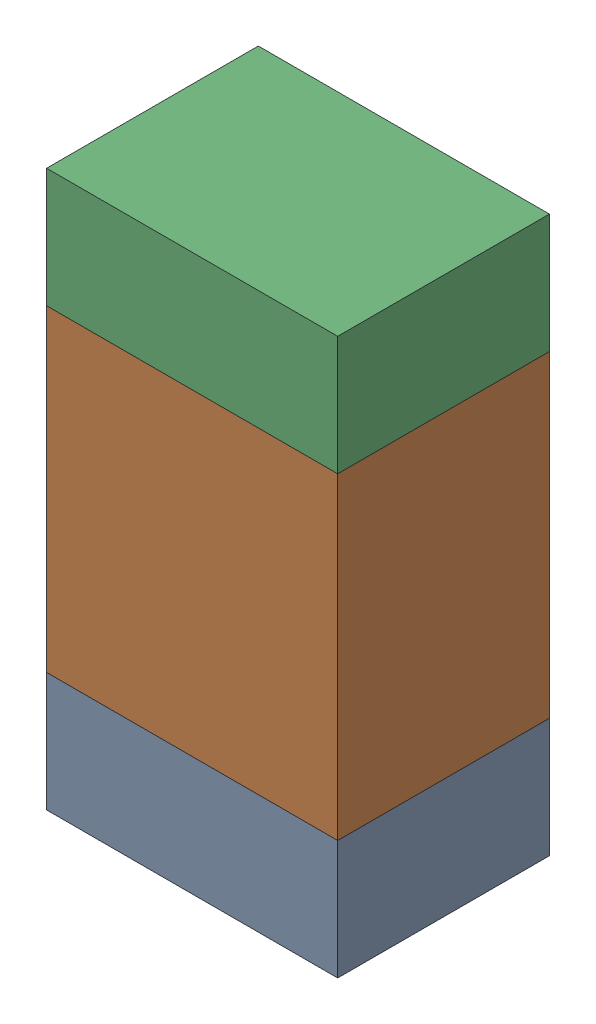
SolidWorks assembly R301_1PCB, configuration Default. Lengths in mm.
Overall size (0.55 1.05 0.4).
6 component instances, 2 part files, 0 mates.
Components (placement in the parent):
- 846483288-1: 846483288 [Default] at (154.4001 108.0874 0) size (0.55 0.22 0.4)
  - Extruded_12-1: Extruded_12 [Default] at origin size (0.55 0.22 0.4)
- 846483424-1: 846483424 [Default] at (154.4001 108.4999 0) size (0.55 0.6 0.4)
  - Extruded_13-1: Extruded_13 [Default] at origin size (0.55 0.6 0.4)
- 846483288-2: 846483288 [Default] at (154.4001 108.9124 0) size (0.55 0.22 0.4)
  - Extruded_12-1: Extruded_12 [Default] at origin size (0.55 0.22 0.4)
